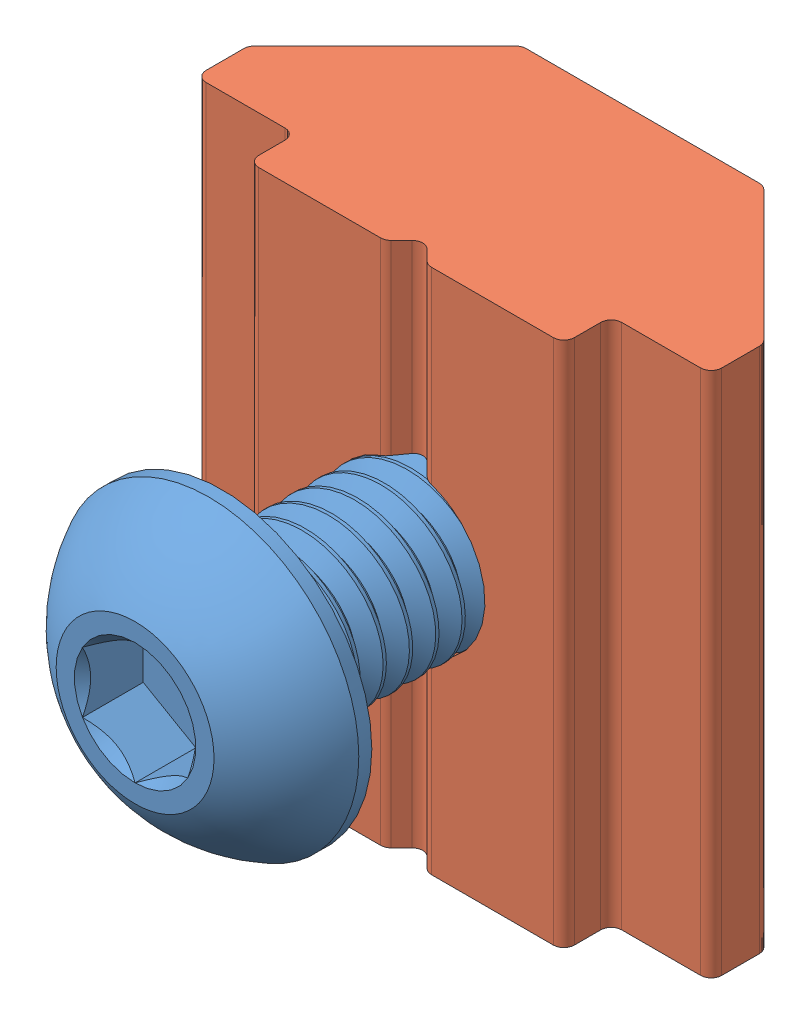
SolidWorks assembly Test Assembly, configuration 8 mm 18-8 Stainless Steel, Passivated. Lengths in mm.
Overall size (9.8 10 9.95).
2 component instances, 2 part files, 4 mates.
Components (placement in the parent):
- Screw-1: Screw [8 mm 18-8 Stainless Steel, Passivated] at origin size (5.7 5.7 9.95)
- T Nut-1: T Nut [M3] at (0 0 -6.05) x (-1 0 0) z (0 1 0)
Mates (geometry in assembly coordinates):
- Concentric1: concentric anti-aligned: circle of M3x8 Pan Head Hex Drive-1; circle of T Nut - Slot 6 - M3-1
- Coincident2: coincident aligned: plane of M3 Button Head Hex Drive Screw-1 through (0 0 -9.65) normal (0 0 -1); plane of T Nut Slot 6-1 through (2.3 -5 -9.65) normal (0 0 -1)
- Coincident3: coordinate: point of M3 Button Head Hex Drive Screw-1
- Distance1: distance = 1 mm aligned: plane of M3 Button Head Hex Drive Screw-1 through (0 0 -11.65) normal (0 0 -1); plane of T Nut Slot 6-1 through (2.3 -5 -12.65) normal (0 0 -1)
